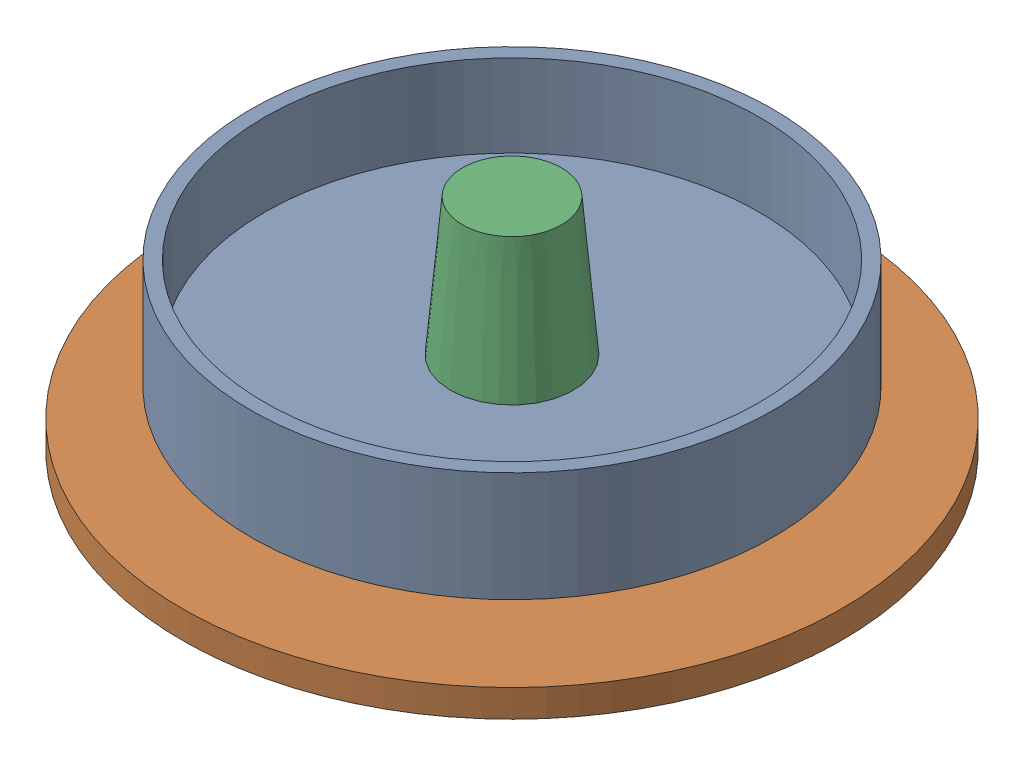
SolidWorks assembly Clamping, configuration Default. Lengths in mm.
Overall size (83.05 35 83.05).
3 component instances, 3 part files, 3 mates.
Components (placement in the parent):
- BS 6-1: BS 6 [Default] at (89.6144 129.993 92.9643) x (0.86441 0 0.502787) z (-0.502787 0 0.86441) size (47.5 10 47.5)
- BS 7-1: BS 7 [Default] at (89.6144 124.993 92.9643) x (0.837169 0 -0.546944) z (0.546944 0 0.837169) size (60 2.5 60)
- BS 8-1: BS 8 [Default] at (89.6144 124.993 92.9643) x (0.67559 0 0.737277) z (0 -1 0) size (15 15 35)
Mates (geometry in assembly coordinates):
- Concentric2: concentric aligned: cylinder of BS 6-1 through (89.6144 124.993 92.9643) axis (0 1 0) radius 5; cone of BS 8-1 through (89.6144 144.993 92.9643) axis (0 1 0)
- Coincident2: coincident anti-aligned: plane of BS 7-1 through (89.6144 124.993 92.9643) normal (0 -1 0); plane of BS 8-1 through (89.6144 124.993 92.9643) normal (0 1 0)
- Concentric1: concentric aligned: cylinder of BS 7-1 through (89.6144 124.993 92.9643) axis (0 1 0) radius 5; cone of BS 8-1 through (89.6144 144.993 92.9643) axis (0 1 0)
